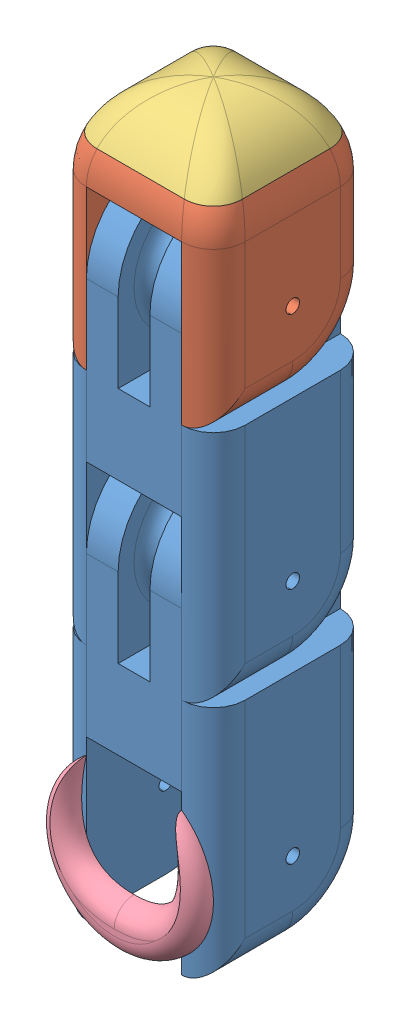
SolidWorks assembly Finger Assembly 4, configuration Default. Lengths in mm.
Overall size (20 90 23.03).
5 component instances, 4 part files, 13 mates.
Components (placement in the parent):
- Finger Body 4-1: Finger Body 4 [Default] at (8.0779 21.877 43.4324) size (20 50 20)
- Finger Body 4-2: Finger Body 4 [Default] at (8.0779 51.877 43.4324) size (20 50 20)
- Finger Top-1: Finger Top [Default] at (8.0779 81.877 43.4324) size (20 24 20)
- Finger Tip-1: Finger Tip [Default] at (8.0779 81.877 43.4324) size (18.77 6 18.77)
- Finger Moon-1: Finger Moon [Default] at (8.0779 11.877 53.4324) x (1 0 0) z (0 -1 0) size (20 3.57 18.53)
Mates (geometry in assembly coordinates):
- Coincident1: coincident anti-aligned: plane of Finger Body 4-1 through (14.0779 41.877 53.4324) normal (1 0 0); plane of Finger Body 4-2 through (14.0779 41.877 33.4324) normal (-1 0 0)
- LimitAngle1: limit planar angle = 1.570796 rad aligned: plane of Finger Body 4-2 through (-1.9221 61.877 53.4324) normal (0 0 1); plane of Finger Body 4-1 through (8.0779 31.877 43.4324) normal (0 1 0)
- Coincident2: coincident anti-aligned: plane of Finger Body 4-2 through (14.0779 71.877 53.4324) normal (1 0 0); plane of Finger Top-1 through (14.0779 71.877 53.4324) normal (-1 0 0)
- Concentric2: concentric aligned: circle of Finger Body-2; circle of Finger Top-1
- LimitAngle2: limit planar angle = 1.570796 rad anti-aligned: plane of Finger Top-1 through (18.0779 85.877 27.2077) normal (0 1 0); plane of Finger Body 4-2 through (-1.9221 61.877 53.4324) normal (0 0 1)
- Concentric3: concentric aligned: circle of Finger Body-1; circle of Finger Body-2
- Coincident5: coincident anti-aligned: plane of Finger Top-1 through (18.0779 85.877 27.2077) normal (0 1 0); plane of Finger Tip-1 through (-1.9221 85.877 53.958) normal (0 -1 0)
- Coincident6: coincident anti-aligned: line of Finger Top-1 through (2.5788 85.877 52.5976) axis (1 0 0); line of Finger Tip-1 through (13.577 85.877 52.5976) axis (-1 0 0)
- Coincident7: coincident anti-aligned: line of Finger Top-1 through (-1.0873 85.877 37.9334) axis (0 0 1); line of Finger Tip-1 through (-1.0873 85.877 48.9315) axis (0 0 -1)
- Coincident8: coincident anti-aligned: plane of Finger Body 4-1 through (-1.9221 31.877 53.4324) normal (0 0 1); plane of Finger Moon-1 through (2.2963 10.7209 53.4324) normal (0 0 -1)
- Coincident9: coincident: line of Finger Body 4-1 through (2.0779 1.877 53.4324) axis (0 1 0); point of Finger Moon-1
- Coincident10: coincident: line of Finger Body 4-1 through (14.0779 1.877 53.4324) axis (0 1 0); point of Finger Moon-1
- Coincident14: coincident anti-aligned: line of Finger Body 4-1 through (2.0779 1.877 43.4324) axis (0 0 1); line of Finger Moon-1 through (2.0779 1.877 53.4324) axis (0 0 -1)
